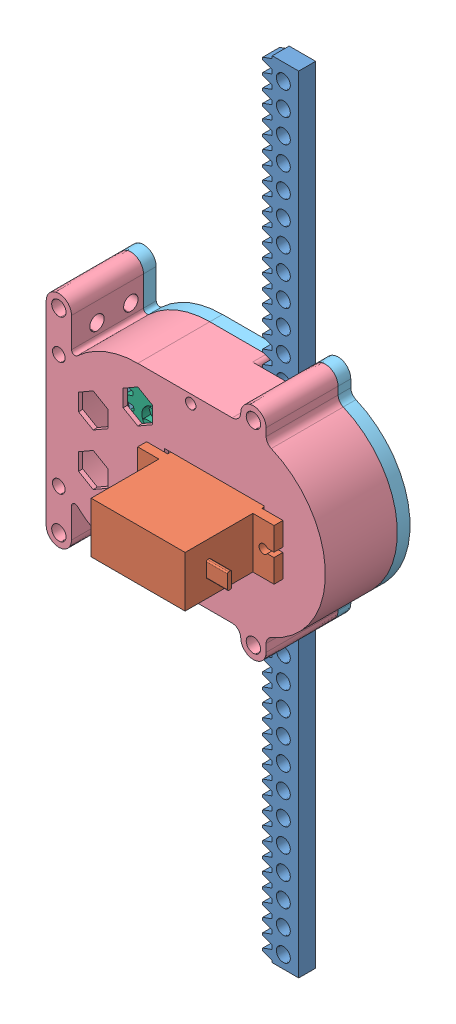
SolidWorks assembly wind-D, configuration Standard. Lengths in mm.
Overall size (65.95 185.5 38.1).
8 component instances, 8 part files, 20 mates.
Components (placement in the parent):
- rack-spur_1M_185-1: rack-spur_1M_185 [ISO - Rack-spur - rectangular 1M 20PA 4FW 6.5PH 185.5L---SAll] at (7.5495 -94.8383 57.2509) x (0 1 0) z (0 0 1) size (185.5 8.5 4)
- TowerProSG92R-1: TowerProSG92R [Standard] at (2.5745 4.7367 72.1509) x (1 0 0) z (0 0 -1) size (32.2 12.01 29.65)
- Gear33-1M-4mm_Servo-1: Gear33-1M-4mm_Servo [ISO - Spur gear 1M 33T 20PA 4FW ---S33A75H50L3.0N] at (7.6995 4.7367 62.5509) x (0 0 -1) z (0.023153 0.999732 0) size (4 34.95 34.98)
- dinstancer-1: dinstancer [Standard] at (7.6995 4.7367 57.2509) size (7.3 7.3 5.3) (hidden)
- groundplate-1: groundplate [Standard] at (-9.908 5.7367 71.1009) x (0 -1 0) z (0 0 -1) size (51.95 65.95 17)
- distancePlate-2: distancePlate [Standard] at (19.9875 4.7494 55.1482) x (0.5 -0.866025 0) z (0 0 -1) size (31.3 28.18 5) (hidden)
- topplate-1: topplate [Standard] at (-9.908 3.7367 51.1009) x (0 1 0) z (0 0 1) size (51.95 65.95 4.5)
- GearNormal-1: GearNormal [Standard] at (-31.6311 0.1975 126.0667) x (0.272448 -0.96217 0) z (0 0 1) size (34.98 34.95 9.5)
Mates (geometry in assembly coordinates):
- Parallel2: parallel aligned: plane of rack-spur_1M_185-1 through (7.5495 90.6617 53.2509) normal (0 1 0); plane of TowerProSG92R-1 through (-13.5255 10.7367 71.1009) normal (0 1 0)
- Deckungsgleich5: coincident anti-aligned: plane of TowerProSG92R-1 through (2.5745 4.7367 62.5509) normal (0 0 -1); plane of Gear33-1M-4mm_Servo-1 through (7.6995 4.7367 62.5509) normal (0 0 1)
- Deckungsgleich6: coincident anti-aligned: plane of TowerProSG92R-1 through (2.5745 4.7367 62.5509) normal (0 0 -1); plane of dinstancer-1 through (7.6995 4.7367 62.5509) normal (0 0 1)
- Konzentrisch4: concentric anti-aligned: cylinder of TowerProSG92R-1 through (7.6995 4.7367 59.5509) axis (0 0 1) radius 2; cylinder of dinstancer-1 through (7.6995 4.7367 62.5509) axis (0 0 -1) radius 2.5
- Deckungsgleich8: coincident anti-aligned: plane of rack-spur_1M_185-1 through (0.0495 -94.8383 57.2509) normal (0 0 1); plane of dinstancer-1 through (7.6995 4.7367 57.2509) normal (0 0 -1)
- Deckungsgleich11: coincident anti-aligned: plane of TowerProSG92R-1 through (2.5745 4.7367 71.1009) normal (0 0 -1); plane of groundplate-1 through (-9.908 5.7367 71.1009) normal (0 0 1)
- Parallel5: parallel aligned: plane of TowerProSG92R-1 through (-13.5255 10.7367 71.1009) normal (0 1 0); plane of groundplate-1 through (-9.908 25.7367 54.1009) normal (0 1 0)
- Deckungsgleich13: coincident anti-aligned: plane of TowerProSG92R-1 through (2.5745 4.7367 71.1009) normal (0 0 -1); plane of groundplate-1 through (-9.908 5.7367 71.1009) normal (0 0 1)
- Konzentrisch9: concentric anti-aligned: cylinder of Gear33-1M-4mm_Servo-1 through (7.6995 4.7367 62.5509) axis (0 0 -1) radius 4.15; cylinder of distancePlate-2 through (7.6995 4.7367 52.1482) axis (0 0 1) radius 1.5
- Konzentrisch10: concentric aligned: cylinder of TowerProSG92R-1 through (7.6995 4.7367 62.5509) axis (0 0 1) radius 6; cylinder of distancePlate-2 through (7.6995 4.7367 52.1482) axis (0 0 1) radius 1.5
- Parallel6: parallel aligned: plane of rack-spur_1M_185-1 through (7.5495 90.6617 53.2509) normal (0 1 0); plane of distancePlate-2 through (-11.6005 4.7367 52.1482) normal (0 1 0)
- Abstand2: distance = 0 mm: line of groundplate-1 through (-15.6005 4.7367 70.1009) axis (0 0 -1); line of distancePlate-2 through (-15.6005 4.7367 52.1482) axis (0 0 1)
- Konzentrisch11: concentric anti-aligned: cylinder of groundplate-1 through (11.6995 27.7129 71.1009) axis (0 0 -1) radius 1.7; cylinder of topplate-1 through (11.6995 27.7129 51.1009) axis (0 0 1) radius 1.7
- Deckungsgleich15: coincident anti-aligned: plane of groundplate-1 through (-9.908 5.7367 54.1009) normal (0 0 -1); plane of topplate-1 through (-9.908 3.7367 54.1009) normal (0 0 1)
- Konzentrisch12: concentric anti-aligned: cylinder of groundplate-1 through (11.6995 -18.2395 71.1009) axis (0 0 -1) radius 1.7; cylinder of topplate-1 through (11.6995 -18.2395 51.1009) axis (0 0 1) radius 1.7
- Konzentrisch13: concentric anti-aligned: cylinder of distancePlate-2 through (-15.6005 4.7367 52.1482) axis (0 0 1) radius 1.5; cylinder of GearNormal-1 through (-15.6005 4.7367 107.051) axis (0 0 -1) radius 3
- Deckungsgleich16: coincident aligned: plane of Gear33-1M-4mm_Servo-1 through (7.6995 4.7367 62.5509) normal (0 0 1); plane of GearNormal-1 through (-15.6005 4.7367 62.5509) normal (0 0 1)
- Zahnradverknüpfung2: gear = 13 : 33 mm: circle of Gear33-1M-4mm_Servo-1; cylinder of GearNormal-1 through (-15.6005 4.7367 47.0509) axis (0 0 -1) radius 7.5
- Abstand3: distance = 0.15 mm anti-aligned: plane of groundplate-1 through (8.6995 25.7367 57.3009) normal (-1 0 0); plane of rack-spur_1M_185-1 through (8.5495 -94.8383 53.2509) normal (1 0 0)
- Zahnstange/Ritzel-Verknüpfung2: rack pinion = 35 mm: line of rack-spur_1M_185-1 through (2.2995 -1.035 53.2509) axis (0 1 0); circle of GearNormal-1
